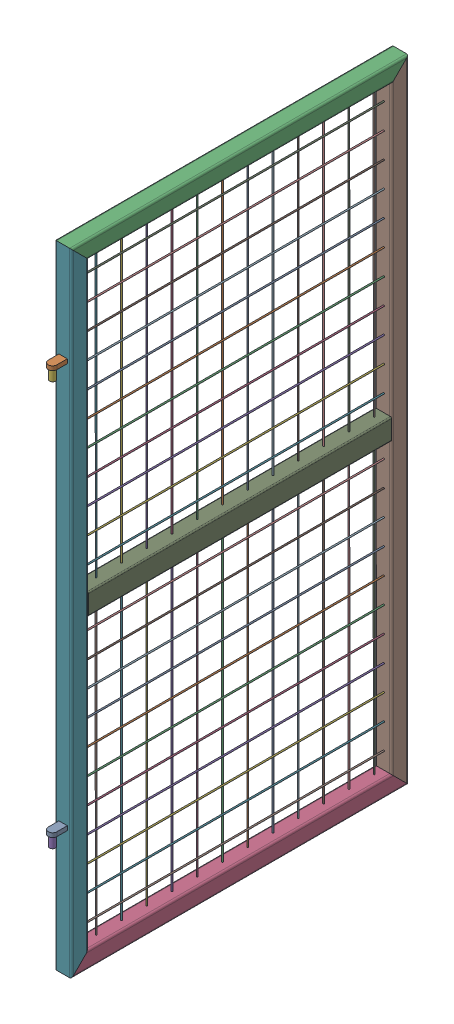
SolidWorks assembly 02.04.00 Uks koost, configuration Default. Lengths in mm.
Overall size (40.01 1500 835).
11 component instances, 6 part files, 3 mates.
Components (placement in the parent):
- 02.04.02Leht_10_S235_35x20-1: 02.04.02Leht_10_S235_35x20 [Default] at origin size (20 10 35)
- 02.04.02Leht_10_S235_35x20-2: 02.04.02Leht_10_S235_35x20 [Default] at (0 1530 0) x (-1 0 0) z (0 0 1) size (20 10 35)
- 02.04.03_Nkt_40x40x2_S235_800-1: 02.04.03_Nkt_40x40x2_S235_800 [Default] at origin size (40 40 800)
- 02.04.03_Nkt_40x40x2_S235_800-2: 02.04.03_Nkt_40x40x2_S235_800 [Default] at (-0.2131 1460 -760) x (1 0.000146 0) z (0 0 -1) size (40 40 800)
- 02.04.04_Toru_14_S235_25-1: 02.04.04_Toru_14_S235_25 [Default] at origin size (14 25 14)
- 02.04.04_Toru_14_S235_25-2: 02.04.04_Toru_14_S235_25 [Default] at (0 960 0) size (14 25 14)
- 02.04.05_Nkt_40x40x2_S235_1500-1: 02.04.05_Nkt_40x40x2_S235_1500 [Default] at origin size (40 1500 40)
- 02.04.05_Nkt_40x40x2_S235_1500-2: 02.04.05_Nkt_40x40x2_S235_1500 [Default] at (0 1460 -760) x (1 0 0.000007) z (0.000007 0 -1) size (40 1500 40)
- 02.04.06_Nkt_50x40x2_S235_720-1: 02.04.06_Nkt_50x40x2_S235_720 [Default] at origin size (40 50 720)
- 02.04.01_Võrk_720x685_S235-1: 02.04.01_Võrk_720x685_S235 [Default] at (-1.5001 -0.0002 0) x (1 0.000146 0) z (0 0 1) size (6 685 720)
- 02.04.01_Võrk_720x685_S235-2: 02.04.01_Võrk_720x685_S235 [Default] at (-1.5001 734.9998 0) x (1 0.000146 0) z (0 0 1) size (6 685 720)
Mates (geometry in assembly coordinates):
- Coincident1: coincident anti-aligned: plane of 02.04.03_Nkt_40x40x2_S235_800-2 through (-15.503 19.9977 0) normal (-0.000146 1 0); plane of 02.04.01_Võrk_suurus_S235-1 through (-1.503 19.9998 -120) normal (0.000146 -1 0)
- Coincident4: coincident anti-aligned: plane of 02.04.05_Nkt_40x40x2_S235_1500-1 through (-15.5 1460 -20) normal (0 0 -1); plane of 02.04.01_Võrk_suurus_S235-1 through (1.4211 540.0002 -20) normal (0 0 1)
- Distance1: distance = 20 mm: cylinder of 02.04.01_Võrk_suurus_S235-1 through (-1.716 1480.0018 -360) axis (0.000146 -1 0) radius 1.5; plane of 02.04.03_Nkt_40x40x2_S235_800-2 through (19.9977 15.5029 0) normal (1 0.000146 0)
